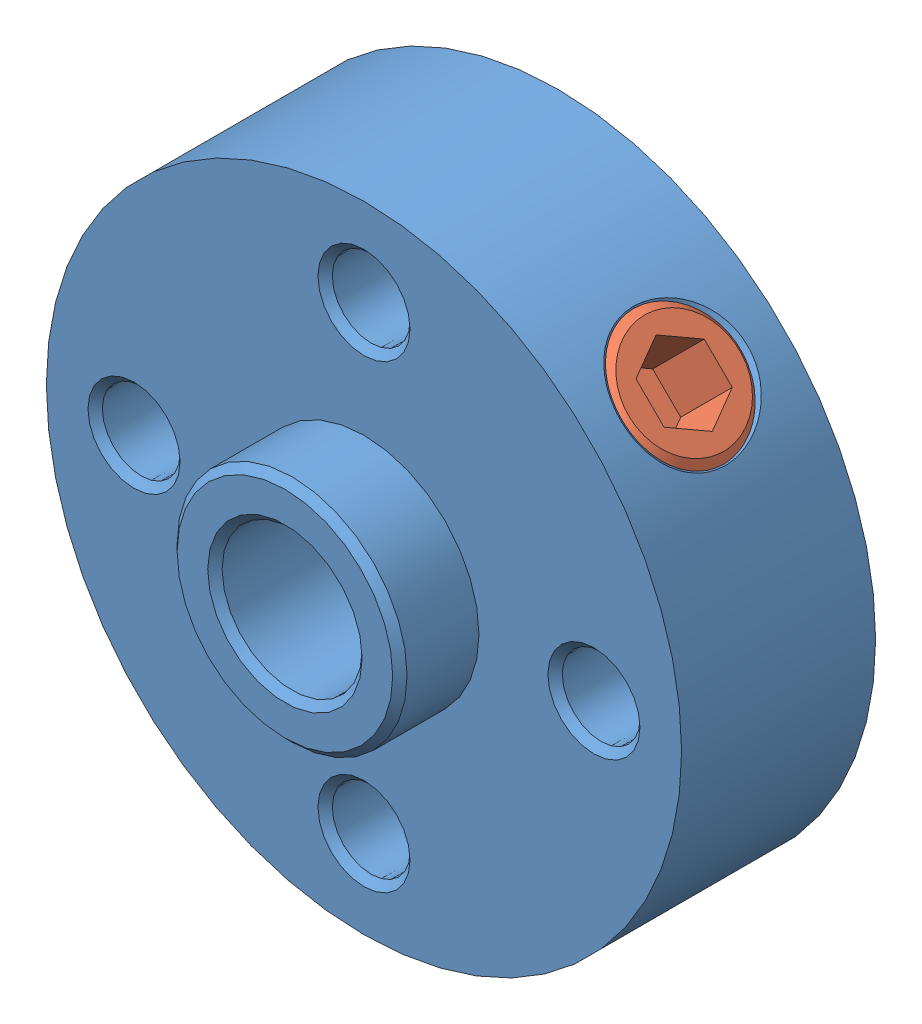
SolidWorks assembly tetrix_739172_virtual, configuration Default. Lengths in mm.
Overall size (22.1 22.1 9.5).
2 component instances, 2 part files, 2 mates.
Components (placement in the parent):
- Copy of tetrix_739172_collar^tetrix_739172-1: Copy of tetrix_739172_collar^tetrix_739172 [Default] at origin size (22.1 22.1 9.5) (virtual)
- Copy of tetrix_739172_screw^tetrix_739172-1: Copy of tetrix_739172_screw^tetrix_739172 [Default] at (7.8135 7.8135 -3.325) x (0.707102 -0.707102 -0.003732) z (-0.002639 0.002639 -0.999993) size (4.83 7.94 4.83) (virtual)
Mates (geometry in assembly coordinates):
- Concentric1: concentric: cylinder of Copy of tetrix_739172_collar^tetrix_739172-1 through (0 0 -3.325) axis (0.707107 0.707107 0) radius 2.02; cylinder of Copy of tetrix_739172_screw^tetrix_739172-1 through (7.8135 7.8135 -3.325) axis (-0.707107 -0.707107 0) radius 2.413
- Tangent1: tangent: cylinder of Copy of tetrix_739172_collar^tetrix_739172-1 through (0 0 0) axis (0 0 1) radius 11.05; plane of Copy of tetrix_739172_screw^tetrix_739172-1 through (9.5198 6.1073 -3.334) normal (0.707107 0.707107 0)
